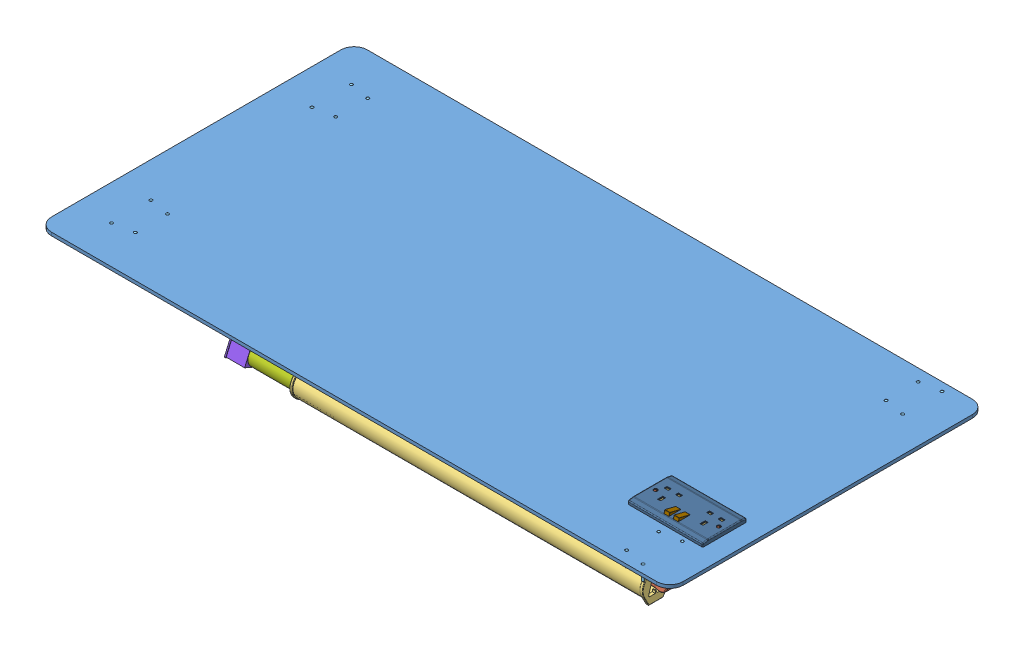
SolidWorks assembly Assem1, configuration Default. Lengths in mm.
Overall size (1219.2 102.1 609.6).
68 component instances, 13 part files, 100 mates.
Components (placement in the parent):
- table_top-1: table_top [Default] at (194.2144 582.9227 1109.7298) size (1219.2 6.35 609.6)
- pied de table rabattable Camar-2: pied de table rabattable Camar [1] at (735.8144 582.9227 1360.2298) x (0 0 -1) z (0 -1 0) size (92 740 81.75) (flexible)
  - base pied-1: base pied [1] at origin size (92 130 55)
  - tube pied-1: tube pied [1] at (0 -353.5 53) size (53 681 70.75)
  - bouton pied-1: bouton pied [1] at (0 -84 18.9792) x (-1 0 0) z (0 1 0) size (28.01 12 50.5)
- pied de table rabattable Camar-3: pied de table rabattable Camar [1] at (735.8144 582.9227 859.2298) x (0 0 -1) z (0 -1 0) size (92 740 81.75) (flexible)
  - base pied-1: base pied [1] at origin size (92 130 55)
  - tube pied-1: tube pied [1] at (0 -353.5 53) size (53 681 70.75)
  - bouton pied-1: bouton pied [1] at (0 -84 18.9792) x (-1 0 0) z (0 1 0) size (28.01 12 50.5)
- pied de table rabattable Camar-4: pied de table rabattable Camar [1] at (-347.3856 582.9227 916.3798) x (0 0 1) z (0 -1 0) size (92 740 81.75) (flexible)
  - base pied-1: base pied [1] at origin size (92 130 55)
  - tube pied-1: tube pied [1] at (0 -353.5 53) size (53 681 70.75)
  - bouton pied-1: bouton pied [1] at (0 -84 18.9792) x (-1 0 0) z (0 1 0) size (28.01 12 50.5)
- pied de table rabattable Camar-5: pied de table rabattable Camar [1] at (-347.3856 582.9227 1303.0798) x (0 0 1) z (0 -1 0) size (92 740 81.75) (flexible)
  - base pied-1: base pied [1] at origin size (92 130 55)
  - tube pied-1: tube pied [1] at (0 -353.5 53) size (53 681 70.75)
  - bouton pied-1: bouton pied [1] at (0 -84 18.9792) x (-1 0 0) z (0 1 0) size (28.01 12 50.5)
- clevis pin with head_is-17: clevis pin with head_is [IS 6863- 4 x 28-A] at (-347.3136 589.2727 954.2818) x (0 -1 0) z (0 0 1) size (29 6 6)
- clevis pin with head_is-18: clevis pin with head_is [IS 6863- 4 x 28-A] at (-308.3856 589.2727 885.3798) x (0 -1 0) z (-0.208333 0 0.978058) size (29 6 6)
- clevis pin with head_is-19: clevis pin with head_is [IS 6863- 4 x 28-A] at (735.7424 589.2727 821.1858) x (0 -1 0) z (0 0 1) size (29 6 6)
- clevis pin with head_is-20: clevis pin with head_is [IS 6863- 4 x 28-A] at (735.7424 589.2727 897.1318) x (0 -1 0) z (0 0 1) size (29 6 6)
- clevis pin with head_is-21: clevis pin with head_is [IS 6863- 4 x 28-A] at (696.8804 589.2727 1329.1858) x (0 -1 0) z (0 0 1) size (29 6 6)
- clevis pin with head_is-22: clevis pin with head_is [IS 6863- 4 x 28-A] at (696.8804 589.2727 1391.1618) x (0 -1 0) z (-0.208333 0 0.978058) size (29 6 6)
- clevis pin with head_is-23: clevis pin with head_is [IS 6863- 4 x 28-A] at (696.8804 589.2727 890.2738) x (0 -1 0) z (0 0 1) size (29 6 6)
- clevis pin with head_is-24: clevis pin with head_is [IS 6863- 4 x 28-A] at (696.8804 589.2727 828.2978) x (0 -1 0) z (0 0 1) size (29 6 6)
- clevis pin with head_is-25: clevis pin with head_is [IS 6863- 4 x 28-A] at (735.7424 589.2727 1322.3278) x (0 -1 0) z (0 0 1) size (29 6 6)
- clevis pin with head_is-26: clevis pin with head_is [IS 6863- 4 x 28-A] at (-308.3856 589.2727 1334.0798) x (0 -1 0) z (0.924225 0 -0.381849) size (29 6 6)
- clevis pin with head_is-27: clevis pin with head_is [IS 6863- 4 x 28-A] at (735.8144 589.2727 1398.2298) x (0 -1 0) z (0 0 1) size (29 6 6)
- clevis pin with head_is-28: clevis pin with head_is [IS 6863- 4 x 28-A] at (-347.3856 589.2727 1265.0798) x (0 -1 0) z (0 0 1) size (29 6 6)
- clevis pin with head_is-29: clevis pin with head_is [IS 6863- 4 x 28-A] at (-308.3856 589.2727 1272.0798) x (0 -1 0) z (0 0 1) size (29 6 6)
- clevis pin with head_is-30: clevis pin with head_is [IS 6863- 4 x 28-A] at (-347.3856 589.2727 1341.0798) x (0 -1 0) z (0 0 1) size (29 6 6)
- clevis pin with head_is-31: clevis pin with head_is [IS 6863- 4 x 28-A] at (-347.3856 589.2727 878.3798) x (0 -1 0) z (0 0 1) size (29 6 6)
- clevis pin with head_is-32: clevis pin with head_is [IS 6863- 4 x 28-A] at (-308.3856 589.2727 947.3798) x (0 -1 0) z (0 0 1) size (29 6 6)
- hexagon flange nut_is-6: hexagon flange nut_is [IS 15581 - M5-N] at (735.7424 577.9227 821.1858) x (1 0 0) z (0 1 0) size (11.8 11.8 5)
- hexagon flange nut_is-7: hexagon flange nut_is [IS 15581 - M5-N] at (735.7424 577.9227 897.1318) x (1 0 0) z (0 1 0) size (11.8 11.8 5)
- hexagon flange nut_is-8: hexagon flange nut_is [IS 15581 - M5-N] at (696.8804 577.9227 890.2738) x (1 0 0) z (0 1 0) size (11.8 11.8 5)
- hexagon flange nut_is-9: hexagon flange nut_is [IS 15581 - M5-N] at (696.8804 577.9227 828.2978) x (1 0 0) z (0 1 0) size (11.8 11.8 5)
- hexagon flange nut_is-10: hexagon flange nut_is [IS 15581 - M5-N] at (735.8144 577.9227 1398.2298) x (-0.837169 0 -0.546944) z (0 1 0) size (11.8 11.8 5)
- hexagon flange nut_is-11: hexagon flange nut_is [IS 15581 - M5-N] at (735.7424 577.9227 1322.3278) x (1 0 0) z (0 1 0) size (11.8 11.8 5)
- hexagon flange nut_is-12: hexagon flange nut_is [IS 15581 - M5-N] at (696.8804 577.9227 1329.1858) x (1 0 0) z (0 1 0) size (11.8 11.8 5)
- hexagon flange nut_is-13: hexagon flange nut_is [IS 15581 - M5-N] at (696.8804 577.9227 1391.1618) x (1 0 0) z (0 1 0) size (11.8 11.8 5)
- hexagon flange nut_is-14: hexagon flange nut_is [IS 15581 - M5-N] at (-347.3856 577.9227 1341.0798) x (-0.837169 0 -0.546944) z (0 1 0) size (11.8 11.8 5)
- hexagon flange nut_is-15: hexagon flange nut_is [IS 15581 - M5-N] at (-308.3856 577.9227 1272.0798) x (1 0 0) z (0 1 0) size (11.8 11.8 5)
- hexagon flange nut_is-16: hexagon flange nut_is [IS 15581 - M5-N] at (-347.3856 577.9227 1265.0798) x (1 0 0) z (0 1 0) size (11.8 11.8 5)
- hexagon flange nut_is-17: hexagon flange nut_is [IS 15581 - M5-N] at (-308.3856 577.9227 885.3798) x (1 0 0) z (0 1 0) size (11.8 11.8 5)
- hexagon flange nut_is-18: hexagon flange nut_is [IS 15581 - M5-N] at (-347.3856 577.9227 878.3798) x (-0.837169 0 -0.546944) z (0 1 0) size (11.8 11.8 5)
- hexagon flange nut_is-19: hexagon flange nut_is [IS 15581 - M5-N] at (-308.3856 577.9227 1334.0798) x (1 0 0) z (0 1 0) size (11.8 11.8 5)
- hexagon flange nut_is-20: hexagon flange nut_is [IS 15581 - M5-N] at (-308.3856 577.9227 947.3798) x (1 0 0) z (0 1 0) size (11.8 11.8 5)
- hexagon flange nut_is-21: hexagon flange nut_is [IS 15581 - M5-N] at (-347.3136 577.9227 954.2818) x (1 0 0) z (0 1 0) size (11.8 11.8 5)
- inner_rod-1: inner_rod [Default] at (121.7376 529.9227 1360.2298) x (0 -0.187821 -0.982203) z (-1 0 0) size (38.1 38.1 203.2)
- inner_rod-2: inner_rod [Default] at (116.8515 529.9227 859.2298) x (0 0.991576 -0.129527) z (-1 0 0) size (38.1 38.1 203.2)
- inner_rod-3: inner_rod [Default] at (261.1307 529.9227 1303.0798) x (0 0.996746 -0.08061) z (1 0 0) size (38.1 38.1 203.2)
- inner_rod-4: inner_rod [Default] at (259.1896 529.9227 916.3798) x (0 0.16511 -0.986275) z (1 0 0) size (38.1 38.1 203.2)
- leg_base_1-1: leg_base_1 [Default] at (464.9296 530.4644 914.7051) x (0 -0.995206 -0.097804) z (-1 0 0) size (40.64 40.64 38.1)
- leg_base_1-2: leg_base_1 [Default] at (466.8707 530.0056 1301.3216) x (0 -0.98596 0.16698) z (-1 0 0) size (40.64 40.64 38.1)
- leg_base_1-3: leg_base_1 [Default] at (-84.0024 528.4927 1361.2561) x (0 -0.396415 -0.918071) z (1 0 0) size (40.64 40.64 38.1)
- leg_base_1-4: leg_base_1 [Default] at (-88.8885 528.2227 859.6862) x (0 -0.047387 -0.998877) z (1 0 0) size (40.64 40.64 38.1)
- Assembled Mains Plug Socket-1: Assembled Mains Plug Socket [Default] at (693.2144 589.2727 1270.4298) x (-1 0 0) z (0 1 0) size (145 85 22)
  - Assembled Mains Plug Socket.STEP-1: Assembled Mains Plug Socket.STEP [Default] at origin size (145 85 22)
    - Switch.STEP-1: Switch.STEP [Default] at (4 10.2944 -0.5423) x (1 0 0) z (0 -0.970296 -0.241922) size (14 10 26)
    - Base Plate.STEP-1: Base Plate.STEP [Default] at origin size (145 85 8)
    - Switch.STEP-2: Switch.STEP [Default] at (-14 10.2944 -0.5423) x (1 0 0) z (0 -0.970296 -0.241922) size (14 10 26)
    - Screw.STEP-1: Screw.STEP [Default] at (61 0 -8) x (1 0 0) z (0 -1 0) size (6 16.96 6)
    - Screw.STEP-2: Screw.STEP [Default] at (-61 0 -8) x (1 0 0) z (0 -1 0) size (6 16.96 6)
    - Black Cover.STEP-1: Black Cover.STEP [Default] at (-56 -22 1) x (1 0 0) z (0 -1 0) size (30 5 40)
    - Black Cover.STEP-2: Black Cover.STEP [Default] at (26 -22 1) x (1 0 0) z (0 -1 0) size (30 5 40)
- rod_holder-1: rod_holder [Default] at (46.8144 529.9227 859.2298) x (0 1 0) z (1 0 0) size (55.88 63.62 12.7)
- rod_holder-2: rod_holder [Default] at (341.6144 529.9227 1303.0798) x (0 1 0) z (-1 0 0) size (55.88 63.62 12.7)
Mates (geometry in assembly coordinates):
- Coincident10: coincident: plane of table_top-1 through (194.2144 582.9227 1109.7298) normal (0 -1 0); plane of pied de table rabattable Camar-2/base pied-1 through (735.8144 582.9227 1360.2298) normal (0 1 0)
- Parallel5: parallel: plane of table_top-1 through (194.2144 589.2727 1414.5298) normal (0 0 1); plane of pied de table rabattable Camar-2/base pied-1 through (676.8144 527.9227 1366.2298) normal (0 0 1)
- Distance6: distance = 50.8 mm: plane of pied de table rabattable Camar-2/base pied-1 through (697.8144 572.9227 1363.7298) normal (0 0 1); plane of table_top-1 through (194.2144 589.2727 1414.5298) normal (0 0 1)
- Distance7: distance = 127 mm: plane of pied de table rabattable Camar-2/base pied-1 through (676.8144 527.9227 1366.2298) normal (-1 0 0); plane of table_top-1 through (803.8144 589.2727 1109.7298) normal (1 0 0)
- Coincident14: coincident: plane of table_top-1 through (194.2144 582.9227 1109.7298) normal (0 -1 0); plane of pied de table rabattable Camar-3/base pied-1 through (735.8144 582.9227 859.2298) normal (0 1 0)
- Distance8: distance = 50.8 mm: plane of pied de table rabattable Camar-3/base pied-1 through (697.8144 572.9227 855.7298) normal (0 0 -1); plane of table_top-1 through (194.2144 589.2727 804.9298) normal (0 0 -1)
- Distance9: distance = 127 mm: plane of pied de table rabattable Camar-3/base pied-1 through (676.8144 527.9227 865.2298) normal (-1 0 0); plane of table_top-1 through (803.8144 589.2727 1109.7298) normal (1 0 0)
- Coincident17: coincident: plane of table_top-1 through (194.2144 582.9227 1109.7298) normal (0 -1 0); plane of pied de table rabattable Camar-4/base pied-1 through (-347.3856 582.9227 916.3798) normal (0 1 0)
- Distance10: distance = 107.95 mm: plane of pied de table rabattable Camar-4/base pied-1 through (-309.3856 572.9227 912.8798) normal (0 0 -1); plane of table_top-1 through (194.2144 589.2727 804.9298) normal (0 0 -1)
- Distance11: distance = 127 mm: plane of pied de table rabattable Camar-4/base pied-1 through (-288.3856 527.9227 910.3798) normal (1 0 0); plane of table_top-1 through (-415.3856 589.2727 1109.7298) normal (-1 0 0)
- Coincident20: coincident: plane of table_top-1 through (194.2144 582.9227 1109.7298) normal (0 -1 0); plane of pied de table rabattable Camar-5/base pied-1 through (-347.3856 582.9227 1303.0798) normal (0 1 0)
- Distance12: distance = 107.95 mm: plane of pied de table rabattable Camar-5/base pied-1 through (-309.3856 572.9227 1306.5798) normal (0 0 1); plane of table_top-1 through (194.2144 589.2727 1414.5298) normal (0 0 1)
- Distance13: distance = 127 mm: plane of pied de table rabattable Camar-5/base pied-1 through (-288.3856 527.9227 1297.0798) normal (1 0 0); plane of table_top-1 through (-415.3856 589.2727 1109.7298) normal (-1 0 0)
- Concentric14: concentric: cylinder of table_top-1 through (-347.3136 589.2727 954.2818) axis (0 -1 0) radius 2.794; cylinder of clevis pin with head_is-17 through (-347.3136 589.2727 954.2818) axis (0 1 0) radius 2
- Concentric15: concentric: cylinder of pied de table rabattable Camar-4/base pied-1 through (-308.3856 572.9227 947.3798) axis (0 -1 0) radius 2.75; cylinder of clevis pin with head_is-32 through (-308.3856 589.2727 947.3798) axis (0 1 0) radius 2
- Concentric16: concentric: cylinder of pied de table rabattable Camar-4/base pied-1 through (-347.3856 572.9227 878.3798) axis (0 -1 0) radius 2.75; cylinder of clevis pin with head_is-31 through (-347.3856 589.2727 878.3798) axis (0 1 0) radius 2
- Concentric17: concentric: cylinder of pied de table rabattable Camar-4/base pied-1 through (-308.3856 572.9227 885.3798) axis (0 -1 0) radius 2.75; cylinder of clevis pin with head_is-18 through (-308.3856 589.2727 885.3798) axis (0 1 0) radius 2
- Concentric18: concentric: cylinder of pied de table rabattable Camar-5/base pied-1 through (-308.3856 572.9227 1334.0798) axis (0 -1 0) radius 2.75; cylinder of clevis pin with head_is-26 through (-308.3856 589.2727 1334.0798) axis (0 1 0) radius 2
- Concentric19: concentric: cylinder of pied de table rabattable Camar-5/base pied-1 through (-347.3856 572.9227 1341.0798) axis (0 -1 0) radius 2.75; cylinder of clevis pin with head_is-30 through (-347.3856 589.2727 1341.0798) axis (0 1 0) radius 2
- Concentric20: concentric: cylinder of pied de table rabattable Camar-5/base pied-1 through (-308.3856 572.9227 1272.0798) axis (0 -1 0) radius 2.75; cylinder of clevis pin with head_is-29 through (-308.3856 589.2727 1272.0798) axis (0 1 0) radius 2
- Concentric21: concentric: cylinder of pied de table rabattable Camar-5/base pied-1 through (-347.3856 572.9227 1265.0798) axis (0 -1 0) radius 2.75; cylinder of clevis pin with head_is-28 through (-347.3856 589.2727 1265.0798) axis (0 1 0) radius 2
- Concentric22: concentric: cylinder of pied de table rabattable Camar-2/base pied-1 through (735.8144 572.9227 1398.2298) axis (0 -1 0) radius 2.75; cylinder of clevis pin with head_is-27 through (735.8144 589.2727 1398.2298) axis (0 1 0) radius 2
- Concentric23: concentric: cylinder of table_top-1 through (696.8804 589.2727 1391.1618) axis (0 -1 0) radius 2.794; cylinder of clevis pin with head_is-22 through (696.8804 589.2727 1391.1618) axis (0 1 0) radius 2
- Concentric24: concentric: cylinder of table_top-1 through (735.7424 589.2727 1322.3278) axis (0 -1 0) radius 2.794; cylinder of clevis pin with head_is-25 through (735.7424 589.2727 1322.3278) axis (0 1 0) radius 2
- Concentric25: concentric: cylinder of table_top-1 through (696.8804 589.2727 1329.1858) axis (0 -1 0) radius 2.794; cylinder of clevis pin with head_is-21 through (696.8804 589.2727 1329.1858) axis (0 1 0) radius 2
- Concentric26: concentric: cylinder of table_top-1 through (735.7424 589.2727 897.1318) axis (0 -1 0) radius 2.794; cylinder of clevis pin with head_is-20 through (735.7424 589.2727 897.1318) axis (0 1 0) radius 2
- Concentric27: concentric: cylinder of table_top-1 through (735.7424 589.2727 821.1858) axis (0 -1 0) radius 2.794; cylinder of clevis pin with head_is-19 through (735.7424 589.2727 821.1858) axis (0 1 0) radius 2
- Concentric28: concentric: cylinder of table_top-1 through (696.8804 589.2727 828.2978) axis (0 -1 0) radius 2.794; cylinder of clevis pin with head_is-24 through (696.8804 589.2727 828.2978) axis (0 1 0) radius 2
- Concentric29: concentric: cylinder of table_top-1 through (696.8804 589.2727 890.2738) axis (0 -1 0) radius 2.794; cylinder of clevis pin with head_is-23 through (696.8804 589.2727 890.2738) axis (0 1 0) radius 2
- Coincident29: coincident: plane of table_top-1 through (194.2144 589.2727 1109.7298) normal (0 1 0); plane of clevis pin with head_is-17 through (-347.3136 589.2727 954.2818) normal (0 1 0)
- Coincident30: coincident: plane of table_top-1 through (194.2144 589.2727 1109.7298) normal (0 1 0); plane of clevis pin with head_is-32 through (-308.3856 589.2727 947.3798) normal (0 1 0)
- Coincident31: coincident: plane of table_top-1 through (194.2144 589.2727 1109.7298) normal (0 1 0); plane of clevis pin with head_is-31 through (-347.3856 589.2727 878.3798) normal (0 1 0)
- Coincident32: coincident: plane of table_top-1 through (194.2144 589.2727 1109.7298) normal (0 1 0); plane of clevis pin with head_is-18 through (-308.3856 589.2727 885.3798) normal (0 1 0)
- Coincident33: coincident: plane of table_top-1 through (194.2144 589.2727 1109.7298) normal (0 1 0); plane of clevis pin with head_is-30 through (-347.3856 589.2727 1341.0798) normal (0 1 0)
- Coincident34: coincident: plane of table_top-1 through (194.2144 589.2727 1109.7298) normal (0 1 0); plane of clevis pin with head_is-28 through (-347.3856 589.2727 1265.0798) normal (0 1 0)
- Coincident35: coincident: plane of table_top-1 through (194.2144 589.2727 1109.7298) normal (0 1 0); plane of clevis pin with head_is-29 through (-308.3856 589.2727 1272.0798) normal (0 1 0)
- Coincident36: coincident: plane of table_top-1 through (194.2144 589.2727 1109.7298) normal (0 1 0); plane of clevis pin with head_is-20 through (735.7424 589.2727 897.1318) normal (0 1 0)
- Coincident37: coincident: plane of table_top-1 through (194.2144 589.2727 1109.7298) normal (0 1 0); plane of clevis pin with head_is-23 through (696.8804 589.2727 890.2738) normal (0 1 0)
- Coincident38: coincident: plane of table_top-1 through (194.2144 589.2727 1109.7298) normal (0 1 0); plane of clevis pin with head_is-19 through (735.7424 589.2727 821.1858) normal (0 1 0)
- Coincident39: coincident: plane of table_top-1 through (194.2144 589.2727 1109.7298) normal (0 1 0); plane of clevis pin with head_is-24 through (696.8804 589.2727 828.2978) normal (0 1 0)
- Coincident40: coincident: plane of table_top-1 through (194.2144 589.2727 1109.7298) normal (0 1 0); plane of clevis pin with head_is-22 through (696.8804 589.2727 1391.1618) normal (0 1 0)
- Coincident41: coincident: plane of table_top-1 through (194.2144 589.2727 1109.7298) normal (0 1 0); plane of clevis pin with head_is-21 through (696.8804 589.2727 1329.1858) normal (0 1 0)
- Coincident42: coincident: plane of table_top-1 through (194.2144 589.2727 1109.7298) normal (0 1 0); plane of clevis pin with head_is-25 through (735.7424 589.2727 1322.3278) normal (0 1 0)
- Coincident43: coincident: plane of table_top-1 through (194.2144 589.2727 1109.7298) normal (0 1 0); plane of clevis pin with head_is-27 through (735.8144 589.2727 1398.2298) normal (0 1 0)
- Coincident44: coincident: plane of pied de table rabattable Camar-3/base pied-1 through (735.8144 577.9227 818.4798) normal (0 -1 0); plane of hexagon flange nut_is-6 through (735.7424 577.9227 816.567) normal (0 1 0)
- Concentric31: concentric: cylinder of clevis pin with head_is-19 through (735.7424 589.2727 821.1858) axis (0 1 0) radius 2; cylinder of hexagon flange nut_is-6 through (735.7424 572.9227 821.1858) axis (0 1 0) radius 2.1
- Coincident45: coincident: plane of pied de table rabattable Camar-3/base pied-1 through (735.8144 577.9227 894.4798) normal (0 -1 0); plane of hexagon flange nut_is-7 through (735.7424 577.9227 892.513) normal (0 1 0)
- Coincident46: coincident: plane of pied de table rabattable Camar-3/base pied-1 through (696.8144 577.9227 887.4798) normal (0 -1 0); plane of hexagon flange nut_is-8 through (696.8804 577.9227 885.655) normal (0 1 0)
- Coincident47: coincident: plane of pied de table rabattable Camar-3/base pied-1 through (696.8144 577.9227 825.4798) normal (0 -1 0); plane of hexagon flange nut_is-9 through (696.8804 577.9227 823.679) normal (0 1 0)
- Coincident48: coincident: plane of pied de table rabattable Camar-2/base pied-1 through (735.8144 577.9227 1395.4798) normal (0 -1 0); plane of hexagon flange nut_is-10 through (733.2881 577.9227 1402.0965) normal (0 1 0)
- Coincident49: coincident: plane of pied de table rabattable Camar-2/base pied-1 through (696.8144 577.9227 1388.4798) normal (0 -1 0); plane of hexagon flange nut_is-13 through (696.8804 577.9227 1386.543) normal (0 1 0)
- Coincident50: coincident: plane of pied de table rabattable Camar-2/base pied-1 through (735.8144 577.9227 1319.4798) normal (0 -1 0); plane of hexagon flange nut_is-11 through (735.7424 577.9227 1317.709) normal (0 1 0)
- Coincident51: coincident: plane of pied de table rabattable Camar-2/base pied-1 through (696.8144 577.9227 1326.4798) normal (0 -1 0); plane of hexagon flange nut_is-12 through (696.8804 577.9227 1324.567) normal (0 1 0)
- Coincident52: coincident: plane of pied de table rabattable Camar-4/base pied-1 through (-381.853 577.9227 903.1298) normal (0 -1 0); plane of hexagon flange nut_is-18 through (-349.9119 577.9227 882.2465) normal (0 1 0)
- Coincident53: coincident: plane of pied de table rabattable Camar-5/base pied-1 through (-381.853 577.9227 1321.8298) normal (0 -1 0); plane of hexagon flange nut_is-14 through (-349.9119 577.9227 1344.9465) normal (0 1 0)
- Coincident54: coincident: plane of pied de table rabattable Camar-4/base pied-1 through (-347.3856 577.9227 957.1298) normal (0 -1 0); plane of hexagon flange nut_is-21 through (-347.3136 577.9227 949.663) normal (0 1 0)
- Coincident55: coincident: plane of pied de table rabattable Camar-4/base pied-1 through (-308.3856 577.9227 888.1298) normal (0 -1 0); plane of hexagon flange nut_is-20 through (-308.3856 577.9227 942.761) normal (0 1 0)
- Coincident56: coincident: plane of pied de table rabattable Camar-5/base pied-1 through (-308.3856 577.9227 1336.8298) normal (0 -1 0); plane of hexagon flange nut_is-19 through (-308.3856 577.9227 1329.461) normal (0 1 0)
- Coincident57: coincident: plane of pied de table rabattable Camar-5/base pied-1 through (-347.3856 577.9227 1343.8298) normal (0 -1 0); plane of hexagon flange nut_is-17 through (-308.3856 577.9227 880.761) normal (0 1 0)
- Coincident58: coincident: plane of pied de table rabattable Camar-5/base pied-1 through (-347.3856 577.9227 1267.8298) normal (0 -1 0); plane of hexagon flange nut_is-16 through (-347.3856 577.9227 1260.461) normal (0 1 0)
- Coincident59: coincident: plane of pied de table rabattable Camar-5/base pied-1 through (-308.3856 577.9227 1274.8298) normal (0 -1 0); plane of hexagon flange nut_is-15 through (-308.3856 577.9227 1267.461) normal (0 1 0)
- Concentric32: concentric: cylinder of clevis pin with head_is-30 through (-347.3856 589.2727 1341.0798) axis (0 1 0) radius 2; cylinder of hexagon flange nut_is-14 through (-347.3856 572.9227 1341.0798) axis (0 1 0) radius 2.1
- Concentric33: concentric: cylinder of clevis pin with head_is-28 through (-347.3856 589.2727 1265.0798) axis (0 1 0) radius 2; cylinder of hexagon flange nut_is-16 through (-347.3856 572.9227 1265.0798) axis (0 1 0) radius 2.1
- Concentric34: concentric: cylinder of clevis pin with head_is-29 through (-308.3856 589.2727 1272.0798) axis (0 1 0) radius 2; circle of hexagon flange nut_is-15
- Concentric35: concentric: cylinder of clevis pin with head_is-26 through (-308.3856 589.2727 1334.0798) axis (0 1 0) radius 2; cylinder of hexagon flange nut_is-19 through (-308.3856 572.9227 1334.0798) axis (0 1 0) radius 2.1
- Concentric36: concentric: cylinder of clevis pin with head_is-18 through (-308.3856 589.2727 885.3798) axis (0 1 0) radius 2; circle of hexagon flange nut_is-17
- Concentric37: concentric: cylinder of clevis pin with head_is-31 through (-347.3856 589.2727 878.3798) axis (0 1 0) radius 2; circle of hexagon flange nut_is-18
- Concentric38: concentric: cylinder of clevis pin with head_is-17 through (-347.3136 589.2727 954.2818) axis (0 1 0) radius 2; cylinder of hexagon flange nut_is-21 through (-347.3136 572.9227 954.2818) axis (0 1 0) radius 2.1
- Concentric39: concentric: cylinder of clevis pin with head_is-24 through (696.8804 589.2727 828.2978) axis (0 1 0) radius 2; circle of hexagon flange nut_is-9
- Concentric40: concentric: cylinder of clevis pin with head_is-20 through (735.7424 589.2727 897.1318) axis (0 1 0) radius 2; cylinder of hexagon flange nut_is-7 through (735.7424 572.9227 897.1318) axis (0 1 0) radius 2.1
- Concentric41: concentric: cylinder of clevis pin with head_is-23 through (696.8804 589.2727 890.2738) axis (0 1 0) radius 2; cylinder of hexagon flange nut_is-8 through (696.8804 572.9227 890.2738) axis (0 1 0) radius 2.1
- Concentric42: concentric: cylinder of clevis pin with head_is-27 through (735.8144 589.2727 1398.2298) axis (0 1 0) radius 2; cylinder of hexagon flange nut_is-10 through (735.8144 572.9227 1398.2298) axis (0 1 0) radius 2.1
- Concentric43: concentric: cylinder of clevis pin with head_is-22 through (696.8804 589.2727 1391.1618) axis (0 1 0) radius 2; cylinder of hexagon flange nut_is-13 through (696.8804 572.9227 1391.1618) axis (0 1 0) radius 2.1
- Concentric44: concentric: cylinder of clevis pin with head_is-25 through (735.7424 589.2727 1322.3278) axis (0 1 0) radius 2; cylinder of hexagon flange nut_is-11 through (735.7424 572.9227 1322.3278) axis (0 1 0) radius 2.1
- Concentric45: concentric: cylinder of clevis pin with head_is-21 through (696.8804 589.2727 1329.1858) axis (0 1 0) radius 2; circle of hexagon flange nut_is-12
- Concentric46: concentric: cylinder of clevis pin with head_is-32 through (-308.3856 589.2727 947.3798) axis (0 1 0) radius 2; circle of hexagon flange nut_is-20
- Coincident60: coincident: plane of table_top-1 through (194.2144 589.2727 1109.7298) normal (0 1 0); plane of clevis pin with head_is-26 through (-308.3856 589.2727 1334.0798) normal (0 1 0)
- Concentric47: concentric: cylinder of pied de table rabattable Camar-2/tube pied-1 through (722.8144 529.9227 1360.2298) axis (1 0 0) radius 20.5; cylinder of inner_rod-1 through (-81.4624 529.9227 1360.2298) axis (1 0 0) radius 19.05
- Concentric48: concentric: cylinder of pied de table rabattable Camar-5/tube pied-1 through (-334.3856 529.9227 1303.0798) axis (-1 0 0) radius 20.5; cylinder of inner_rod-3 through (464.3307 529.9227 1303.0798) axis (-1 0 0) radius 19.05
- Concentric49: concentric: cylinder of pied de table rabattable Camar-3/tube pied-1 through (722.8144 529.9227 859.2298) axis (1 0 0) radius 20.5; cylinder of inner_rod-2 through (-86.3485 529.9227 859.2298) axis (1 0 0) radius 19.05
- Concentric51: concentric: cylinder of pied de table rabattable Camar-4/tube pied-1 through (-334.3856 529.9227 916.3798) axis (-1 0 0) radius 20.5; cylinder of inner_rod-4 through (462.3896 529.9227 916.3798) axis (-1 0 0) radius 19.05
- LimitDistance1: limit distance = 128.1629 mm: plane of inner_rod-2 through (-86.3485 529.9227 859.2298) normal (-1 0 0); plane of pied de table rabattable Camar-3/tube pied-1 through (41.8144 529.9227 885.7298) normal (-1 0 0)
- LimitDistance2: limit distance = 123.2768 mm: plane of inner_rod-1 through (-81.4624 529.9227 1360.2298) normal (-1 0 0); plane of pied de table rabattable Camar-2/tube pied-1 through (41.8144 529.9227 1386.7298) normal (-1 0 0)
- LimitDistance3: limit distance = 115.7752 mm: plane of pied de table rabattable Camar-4/tube pied-1 through (346.6144 529.9227 889.8798) normal (1 0 0); plane of inner_rod-4 through (462.3896 529.9227 916.3798) normal (1 0 0)
- LimitDistance4: limit distance = 117.7163 mm: plane of inner_rod-3 through (464.3307 529.9227 1303.0798) normal (1 0 0); plane of pied de table rabattable Camar-5/tube pied-1 through (346.6144 529.9227 1276.5798) normal (1 0 0)
- Concentric52: concentric: cylinder of inner_rod-4 through (462.3896 529.9227 916.3798) axis (-1 0 0) radius 19.05; cylinder of leg_base_1-1 through (462.3896 529.9227 916.3798) axis (-1 0 0) radius 19.177
- Concentric53: concentric: cylinder of inner_rod-3 through (464.3307 529.9227 1303.0798) axis (-1 0 0) radius 19.05; cylinder of leg_base_1-2 through (464.3307 529.9227 1303.0798) axis (-1 0 0) radius 19.177
- Concentric54: concentric: cylinder of inner_rod-2 through (-86.3485 529.9227 859.2298) axis (1 0 0) radius 19.05; cylinder of leg_base_1-4 through (-86.3485 529.9227 859.2298) axis (1 0 0) radius 19.177
- Concentric55: concentric: cylinder of inner_rod-1 through (-81.4624 529.9227 1360.2298) axis (1 0 0) radius 19.05; cylinder of leg_base_1-3 through (-81.4624 529.9227 1360.2298) axis (1 0 0) radius 19.177
- Coincident63: coincident: plane of inner_rod-4 through (462.3896 529.9227 916.3798) normal (1 0 0); plane of leg_base_1-1 through (462.3896 529.9227 916.3798) normal (-1 0 0)
- Coincident64: coincident: plane of inner_rod-3 through (464.3307 529.9227 1303.0798) normal (1 0 0); plane of leg_base_1-2 through (464.3307 529.9227 1303.0798) normal (-1 0 0)
- Coincident65: coincident: plane of inner_rod-1 through (-81.4624 529.9227 1360.2298) normal (-1 0 0); plane of leg_base_1-3 through (-81.4624 529.9227 1360.2298) normal (1 0 0)
- Coincident66: coincident: plane of inner_rod-2 through (-86.3485 529.9227 859.2298) normal (-1 0 0); plane of leg_base_1-4 through (-86.3485 529.9227 859.2298) normal (1 0 0)
- Coincident67: coincident: plane of table_top-1 through (194.2144 589.2727 1109.7298) normal (0 1 0); plane of Assembled Mains Plug Socket-1/Assembled Mains Plug Socket.STEP-1/Base Plate.STEP-1 through (693.2144 589.2727 1270.4298) normal (0 -1 0)
- Distance14: distance = 38.1 mm: line of table_top-1 through (803.8144 589.2727 830.3298) axis (0 0 1); line of Assembled Mains Plug Socket-1/Assembled Mains Plug Socket.STEP-1/Base Plate.STEP-1 through (765.7144 589.2727 1310.9298) axis (0 0 -1)
- Distance15: distance = 101.6 mm: line of table_top-1 through (-389.9856 589.2727 1414.5298) axis (1 0 0); line of Assembled Mains Plug Socket-1/Assembled Mains Plug Socket.STEP-1/Base Plate.STEP-1 through (622.7144 589.2727 1312.9298) axis (1 0 0)
- Concentric57: concentric: cylinder of pied de table rabattable Camar-3/tube pied-1 through (722.8144 529.9227 859.2298) axis (1 0 0) radius 25; cylinder of rod_holder-1 through (59.5144 529.9227 859.2298) axis (-1 0 0) radius 25.019
- Tangent1: tangent: torus of pied de table rabattable Camar-3/tube pied-1; plane of rod_holder-1 through (46.8144 529.9227 859.2298) normal (-1 0 0)
- Concentric58: concentric: cylinder of pied de table rabattable Camar-5/tube pied-1 through (-334.3856 529.9227 1303.0798) axis (-1 0 0) radius 25; cylinder of rod_holder-2 through (328.9144 529.9227 1303.0798) axis (1 0 0) radius 25.019
- Tangent2: tangent: torus of pied de table rabattable Camar-5/tube pied-1; plane of rod_holder-2
